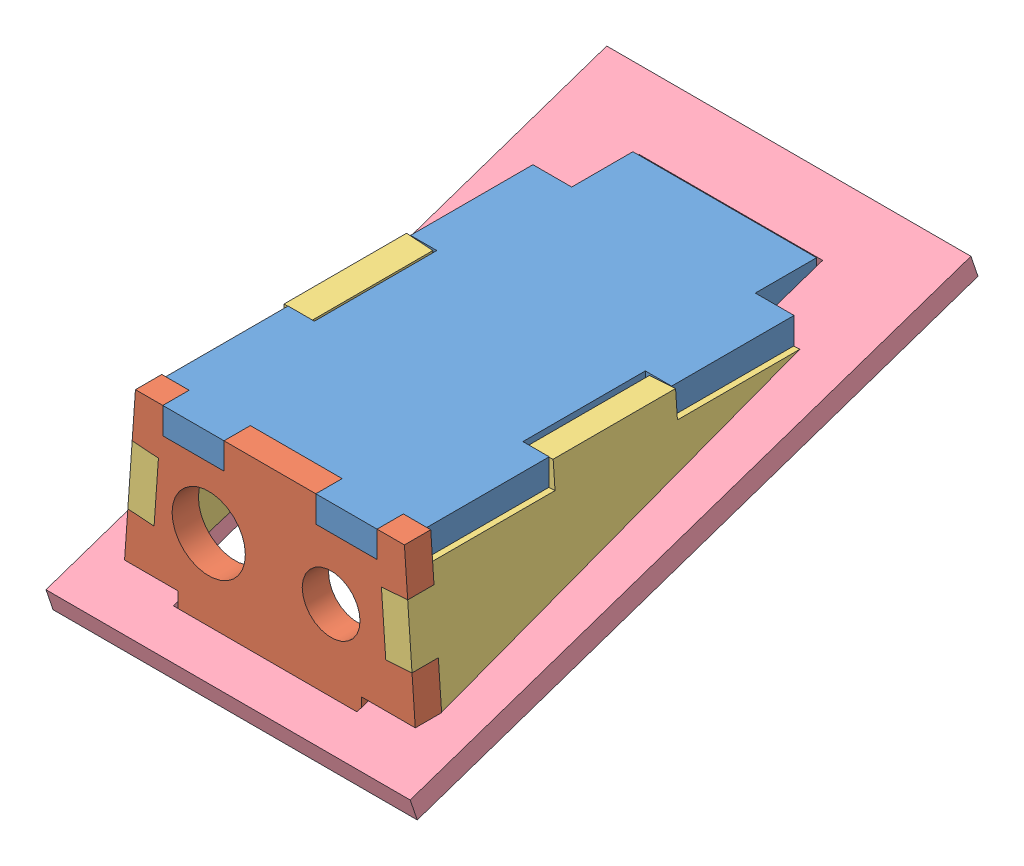
SolidWorks assembly CableBump, configuration Default. Lengths in mm.
Overall size (75.56 58.84 117.81).
5 component instances, 4 part files, 13 mates.
Components (placement in the parent):
- CableBumpTop-1: CableBumpTop [Default] at (44.7195 52.8635 59.2182) size (54.18 5.46 94.36)
- CableBumpFront-1: CableBumpFront [Default] at (44.7195 43.067 97.3182) size (60.32 36.83 5.46)
- CableBumpSide-1: CableBumpSide [Default] at (69.431 26.2396 97.3182) x (-0.023144 0.325314 -0.945323) z (0.997479 0.070964 0) size (82.67 24.85 5.46)
- CableBumpSide-2: CableBumpSide [Default] at (14.5607 26.6271 97.3182) x (0.023144 0.325314 -0.945323) z (0.997479 -0.070964 0) size (82.67 24.85 5.46)
- CableBumpTemplate-1: CableBumpTemplate [Default] at (44.7195 34.3959 60.0829) x (1 0 0) z (0 -0.321679 0.946849) size (75.56 4.57 122.87)
Mates (geometry in assembly coordinates):
- Coincident1: coincident anti-aligned: line of CableBumpTop-1 through (35.1945 58.3245 102.7792) axis (0 0 -1); line of CableBumpFront-1 through (35.1945 58.3245 97.3182) axis (0 0 1)
- Coincident2: coincident anti-aligned: line of CableBumpTop-1 through (35.1945 52.8635 102.7792) axis (-1 0 0); line of CableBumpFront-1 through (22.4945 52.8635 102.7792) axis (1 0 0)
- Coincident3: coincident anti-aligned: line of CableBumpFront-1 through (67.8547 48.3959 102.7792) axis (0.070964 -0.997479 0); line of CableBumpSide-1 through (68.7559 35.7279 102.7792) axis (-0.070964 0.997479 0)
- Coincident6: coincident aligned: line of CableBumpFront-1 through (73.3019 48.7834 97.3182) axis (0 0 1); line of CableBumpSide-1 through (73.3019 48.7834 97.3182) axis (0 0 1)
- Coincident7: coincident anti-aligned: line of CableBumpFront-1 through (20.683 35.7279 102.7792) axis (0.070964 0.997479 0); line of CableBumpSide-2 through (21.5842 48.3959 102.7792) axis (-0.070964 -0.997479 0)
- Coincident8: coincident anti-aligned: line of CableBumpFront-1 through (16.137 48.7834 97.3182) axis (0 0 1); line of CableBumpSide-2 through (16.137 48.7834 102.7792) axis (0 0 -1)
- Coincident9: coincident: plane of CableBumpTop-1 through (17.6304 57.4355 21.4992) normal (0 0 -1); line of ? through (25.6695 54.1935 21.4992) axis (-1 0 0)
- Coincident11: coincident: plane of CableBumpTop-1 through (44.7195 57.4355 59.2182) normal (0 1 0); line of ? through (71.8086 57.4355 18.2754) axis (-1 0 0)
- Coincident13: coincident anti-aligned: plane of CableBumpTop-1 through (63.7695 14.6265 21.4992) normal (1 0 0); plane of ? through (63.7695 57.4355 18.2754) normal (-1 0 0)
- Coincident14: coincident: line of CableBumpFront-1 through (25.6695 21.4945 102.7792) axis (1 0 0); plane of CableBumpTemplate-1 through (25.6695 20.0565 102.2906) normal (0 0.321679 -0.946849)
- Coincident15: coincident: line of CableBumpFront-1 through (63.7695 26.5745 97.3182) axis (1 0 0); plane of CableBumpTemplate-1 through (44.7195 38.7249 61.5537) normal (0 0.946849 0.321679)
- Coincident17: coincident anti-aligned: plane of CableBumpFront-1 through (63.7695 26.5745 58.881) normal (1 0 0); plane of CableBumpTemplate-1 through (63.7695 21.5272 97.9616) normal (-1 0 0)
- Coincident19: coincident: point of CableBumpSide-1; plane of CableBumpTemplate-1 through (44.7195 38.7249 61.5537) normal (0 0.946849 0.321679)
